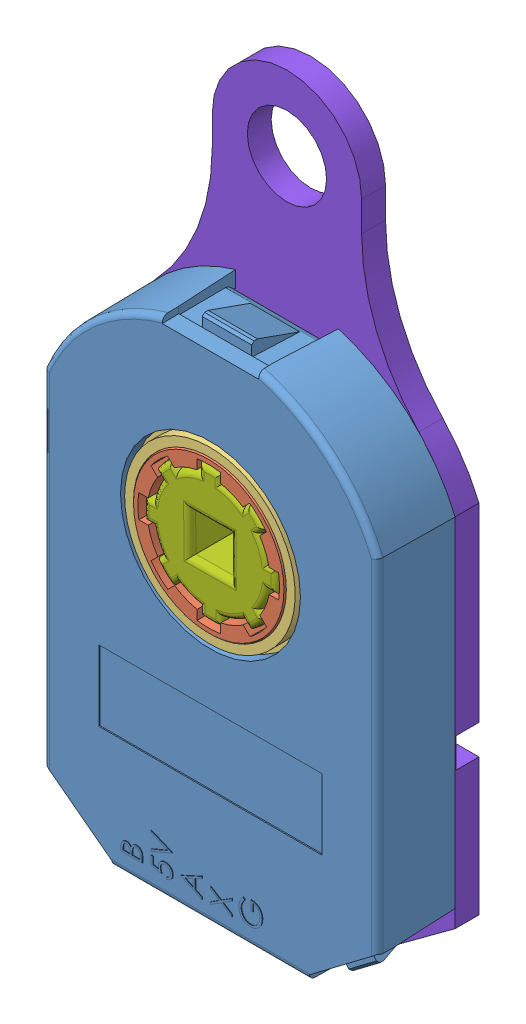
SolidWorks assembly AMT102, configuration Default. Lengths in mm.
Overall size (36.33 59.79 8.68).
8 component instances, 8 part files, 6 mates.
Components (placement in the parent):
- CUI_DEVICES_amt-102-top-cover-rev-i-1: CUI_DEVICES_amt-102-top-cover-rev-i [Default] at (0 0 5.23) x (-1 0 0) z (0 0 -1) size (28.6 43.26 6.55)
- CUI_DEVICES_amt-hub-top-rev-d1-1: CUI_DEVICES_amt-hub-top-rev-d1 [Default] at (0 0 2.13) x (0.999996 0.002864 0) z (0 0 1) size (14 14 5.67)
- CUI_DEVICES_amt-hub-bottom-rev-b-1: CUI_DEVICES_amt-hub-bottom-rev-b [Default] at (0 0 2.43) x (0.999998 -0.001942 0) z (0 0 1) size (17.3 17.3 3.2)
- CUI_DEVICES_receiver-board-1: CUI_DEVICES_receiver-board [Default] at (72.2834 -20.351 3.03) x (-1 0 0) z (0 0 -1) size (26.5 26.62 0.41)
- CUI_DEVICES_rotor-board-rev f-1: CUI_DEVICES_rotor-board-rev f [Default] at (0 0 2.13) x (0.807874 -0.589355 0) z (0 0 1) size (26 26 0.3)
- CUI_DEVICES_transmitter-board amt10(amt-102)-1: CUI_DEVICES_transmitter-board amt10(amt-102) [Default] at (19.1596 -17.1102 1.22) x (-1 0 0) z (0 0 -1) size (26.63 38.43 4.41)
- insert-1: insert [Default] at (0 0 -2.346) x (0.999962 0.008696 0) z (0.008696 -0.999962 0) size (11.43 7.66 11.43)
- plate-1: plate [Default] at (0 0 -3.302) x (1 0 0) z (0 -1 0) size (28.6 3.93 59.79)
Mates (geometry in assembly coordinates):
- Coincident1: coincident anti-aligned: plane of CUI_DEVICES_amt-hub-top-rev-d1-1 through (0 0 1.21) normal (0 0 -1); plane of insert-1 through (0 0 1.21) normal (0 0 1)
- Concentric1: concentric anti-aligned: cone of CUI_DEVICES_amt-hub-top-rev-d1-1 through (0 0 5.38) axis (0 0 1); cylinder of insert-1 through (0 0 1.21) axis (0 0 -1) radius 5.715
- Coincident4: coincident: plane of CUI_DEVICES_amt-hub-top-rev-d1-1 through (-4.2507 2.8163 5.38) normal (0.704971 0.709021 -0.017452); point of insert-1
- Coincident5: coincident: plane of CUI_DEVICES_amt-102-top-cover-rev-i-1 through (0 0 -1.27) normal (0 0 -1); plane of plate-1 through (0 0 -1.27) normal (0 0 1)
- Concentric2: concentric: cylinder of insert-1 through (0 0 1.21) axis (0 0 -1) radius 5.715; cylinder of plate-1 through (0 0 -1.27) axis (0 0 -1) radius 6.477
- Parallel3: parallel: line of CUI_DEVICES_amt-102-top-cover-rev-i-1 through (8.401 -27.8551 4.7387) axis (-1 0 0); plane of plate-1 through (-9.271 -28.0416 -1.27) normal (0 -1 0)
